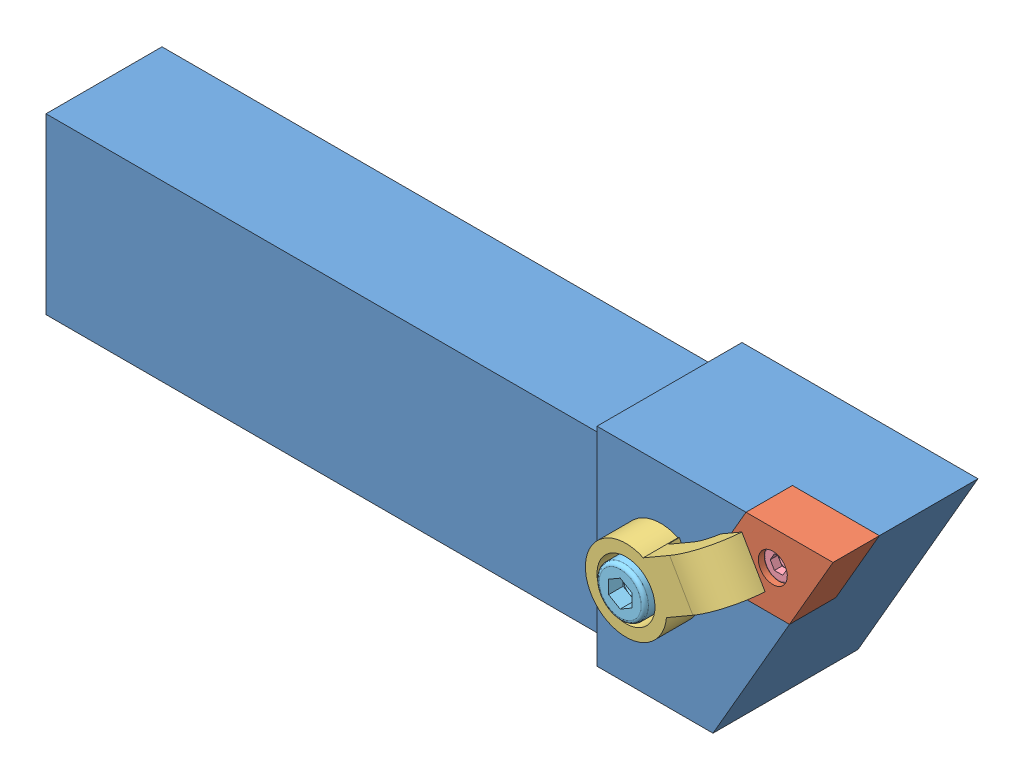
SolidWorks assembly 60度偏刀, configuration 默认. Lengths in mm.
Overall size (144.45 42.34 32).
5 component instances, 4 part files, 10 mates.
Components (placement in the parent):
- 60偏刀刀柄-1: 60偏刀刀柄 [默认] at (-21.8126 2.6791 0) size (140.7 35.85 25)
- 60度偏刀刀片-2: 60度偏刀刀片 [默认] at (57.6325 17.0289 17) x (0.866025 0.5 0) z (0 0 1) size (25.98 15 8)
- 60度偏刀挡片-1: 60度偏刀挡片 [默认] at (42.3835 13.9882 31) x (0.866025 0.5 0) z (0.5 -0.866025 0) size (25.45 12 14)
- hexagon socket head cap screws gb-3: hexagon socket head cap screws gb [GB_FASTENER_SCREWS_HSHCS M3X5-N] at (58.5069 17.5337 24) x (0 0 -1) z (1 0 0) size (8 5.5 5.5)
- hexagon socket head cap screws gb-4: hexagon socket head cap screws gb [GB_FASTENER_SCREWS_HSHCS M5X8-N] at (39.1874 7.5241 32) x (0 0 -1) z (0 -1 0) size (13 8.5 8.5)
Mates (geometry in assembly coordinates):
- 重合3: coincident anti-aligned: plane of 60偏刀刀柄-1 through (46.3825 10.5337 17) normal (0 1 0); plane of 60度偏刀刀片-2 through (46.3825 10.5337 25) normal (0 -1 0)
- 重合4: coincident anti-aligned: plane of 60偏刀刀柄-1 through (53.8825 23.5241 17) normal (0.866025 -0.5 0); plane of 60度偏刀刀片-2 through (53.8825 23.5241 25) normal (-0.866025 0.5 0)
- 重合5: coincident anti-aligned: plane of 60偏刀刀柄-1 through (-21.8126 2.6791 17) normal (0 0 1); plane of 60度偏刀刀片-2 through (57.6325 17.0289 17) normal (0 0 -1)
- 重合6: coincident anti-aligned: circle of 60偏刀刀柄-1; plane of 60度偏刀挡片-1 through (39.1874 7.5241 19) normal (0 0 -1)
- 同心2: concentric aligned: cylinder of 60偏刀刀柄-1 through (39.1874 7.5241 25) axis (0 0 1) radius 5; cylinder of 60度偏刀挡片-1 through (39.1874 7.5241 31) axis (0 0 1) radius 5
- 角度1: planar angle = 0.523599 rad aligned: plane of 60度偏刀挡片-1 through (50.7137 9.56 23.3699) normal (0.5 -0.866025 0); plane of 60偏刀刀柄-1 through (48.1874 -12.3209 0) normal (0.866025 -0.5 0)
- 同心3: concentric aligned: cylinder of 60度偏刀刀片-2 through (58.5069 17.5337 25) axis (0 0 1) radius 1.5; cylinder of hexagon socket head cap screws gb-3 through (58.5069 17.5337 16) axis (0 0 1) radius 1.5
- 重合7: coincident anti-aligned: plane of 60度偏刀刀片-2 through (59.8059 18.2837 21) normal (0 0 1); plane of hexagon socket head cap screws gb-3 through (58.5069 17.5337 21) normal (0 0 -1)
- 同心5: concentric aligned: cylinder of 60度偏刀挡片-1 through (39.1874 7.5241 31) axis (0 0 1) radius 2.5; cylinder of hexagon socket head cap screws gb-4 through (39.1874 7.5241 19) axis (0 0 1) radius 2.5
- 重合8: coincident anti-aligned: plane of 60度偏刀挡片-1 through (41.3525 8.7741 27) normal (0 0 1); plane of hexagon socket head cap screws gb-4 through (39.1874 7.5241 27) normal (0 0 -1)
